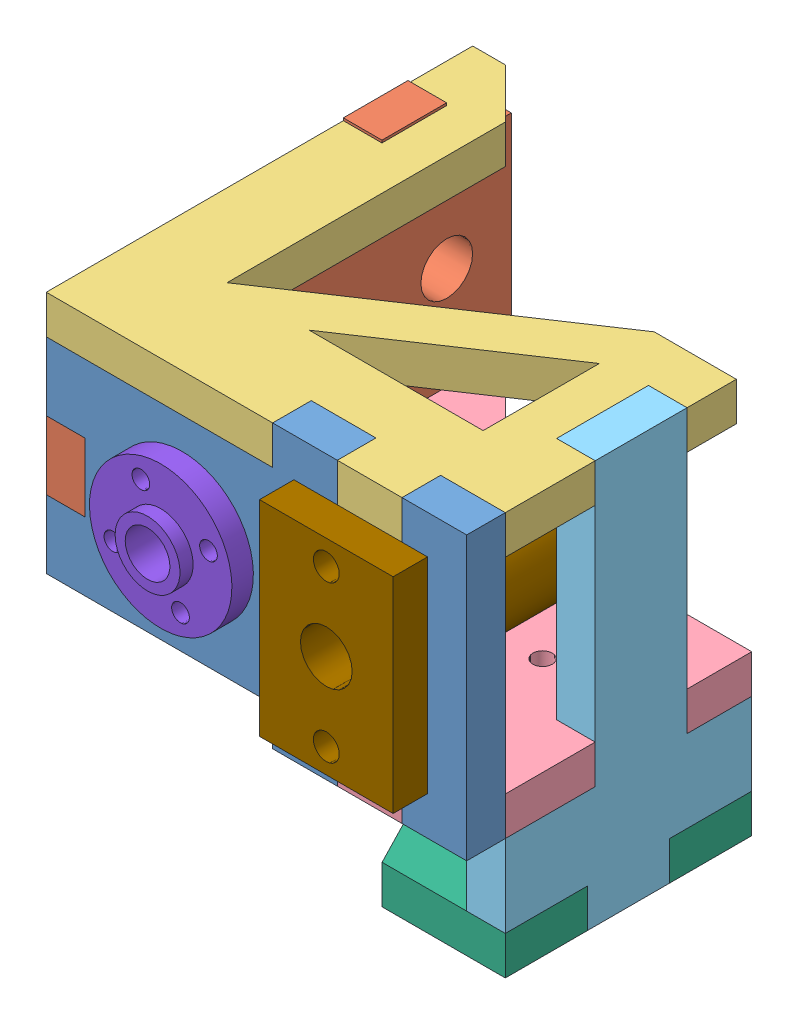
SolidWorks assembly yAssemLeftSide, configuration Default. Lengths in mm.
Overall size (65 62.69 71.28).
9 component instances, 9 part files, 27 mates.
Components (placement in the parent):
- yMountBase-1: yMountBase [Default] at (26.2559 40.0387 54.9751) x (0 -1 0) z (1 0 0) size (42.67 5.97 65)
- xRodHolderFace-1: xRodHolderFace [Default] at (-32.7751 18.9054 49.0061) x (0 1 0) z (-1 0 0) size (44.4 65.93 5.97)
- yBrace-2: yBrace [Default] at (-32.7751 40.0387 19.047) size (65 5.97 65.93)
- yBraceLeft-1: yBraceLeft [Default] at (-32.7751 2.3697 19.047) size (65 5.97 65.93)
- yLeftSideSprocketMount-1: yLeftSideSprocketMount [Default] at (26.2559 -10.3303 49.0061) x (0 1 0) z (0 0 1) size (62.31 5.97 38.1)
- 3mmSprocketHolder-1: 3mmSprocketHolder [Default] at (26.2559 -16.2993 49.0061) x (0 0 -1) z (1 0 0) size (38.1 5.97 26.24)
- 3mmSprocket-1: 3mmSprocket [Default] at (11.0159 -8.2653 28.0061) size (13 8.57 13)
- brassThing-1: brassThing [Default] at (-17.7341 24.1887 58.2951) x (-0.923728 -0.383049 0) z (0.383049 -0.923728 0) size (22.02 10.35 22.02)
- slider-1: slider [Default] at (20.1998 40.0387 60.2951) x (0 -1 0) z (1 0 0) size (31.7 45.2 20.66)
Mates (geometry in assembly coordinates):
- Coincident1: coincident: plane of ? through (18.4701 50.7912 97.883) normal (0 0 1); plane of yMountBase-1 through (26.2559 40.0387 49.0061) normal (0 0 -1)
- Coincident2: coincident: plane of ? through (-20.1799 44.4412 67.924) normal (0 -1 0); plane of yMountBase-1 through (6.2559 45.0387 54.9751) normal (0 1 0)
- Coincident5: coincident: plane of ? through (28.4701 50.7912 97.883) normal (1 0 0); plane of yMountBase-1 through (16.2559 40.0387 54.9751) normal (-1 0 0)
- Coincident6: coincident: plane of ? through (-20.1799 50.7912 67.924) normal (0 1 0); plane of yMountBase-1 through (6.2559 45.0387 54.9751) normal (0 1 0)
- Coincident7: coincident anti-aligned: plane of yMountBase-1 through (26.2559 40.0387 49.0061) normal (0 0 -1); plane of xRodHolderFace-1 through (-38.7441 40.0387 49.0061) normal (0 0 1)
- Coincident8: coincident anti-aligned: plane of yMountBase-1 through (-32.7751 18.9054 49.0061) normal (-1 0 0); plane of xRodHolderFace-1 through (-32.7751 18.9054 49.0061) normal (1 0 0)
- Coincident9: coincident anti-aligned: plane of yMountBase-1 through (-38.7441 18.9054 49.0061) normal (0 1 0); plane of xRodHolderFace-1 through (-38.7441 18.9054 54.9751) normal (0 -1 0)
- Coincident12: coincident anti-aligned: plane of yMountBase-1 through (26.2559 40.0387 49.0061) normal (0 1 0); plane of yBrace-2 through (-32.7751 40.0387 19.047) normal (0 -1 0)
- Coincident13: coincident anti-aligned: plane of xRodHolderFace-1 through (-32.7751 18.9054 49.0061) normal (1 0 0); plane of yBrace-2 through (-32.7751 46.0077 9.047) normal (-1 0 0)
- Coincident14: coincident anti-aligned: plane of xRodHolderFace-1 through (-32.7751 18.9054 49.0061) normal (1 0 0); plane of yBrace-2 through (-32.7751 46.0077 9.047) normal (-1 0 0)
- Coincident15: coincident: line of xRodHolderFace-1 through (-38.7441 46.3887 9.047) axis (0 -1 0); plane of yBrace-2 through (-38.7441 46.0077 9.047) normal (0 0 -1)
- Coincident16: coincident anti-aligned: plane of xRodHolderFace-1 through (-32.7751 18.9054 49.0061) normal (1 0 0); plane of yBraceLeft-1 through (-32.7751 8.3387 9.047) normal (-1 0 0)
- Coincident17: coincident anti-aligned: plane of yMountBase-1 through (26.2559 40.0387 49.0061) normal (0 0 -1); plane of yBraceLeft-1 through (26.2559 8.3387 49.0061) normal (0 0 1)
- Coincident18: coincident aligned: plane of yMountBase-1 through (26.2559 2.3697 54.9751) normal (0 -1 0); plane of yBraceLeft-1 through (-32.7751 2.3697 19.047) normal (0 -1 0)
- Coincident22: coincident anti-aligned: plane of yBraceLeft-1 through (20.2869 -45.5551 35.1061) normal (1 0 0); plane of yLeftSideSprocketMount-1 through (20.2869 -10.3303 49.0061) normal (-1 0 0)
- Coincident23: coincident anti-aligned: plane of yBraceLeft-1 through (26.2559 -45.5551 35.1061) normal (0 0 -1); plane of yLeftSideSprocketMount-1 through (20.2869 2.3697 35.1061) normal (0 0 1)
- Coincident24: coincident anti-aligned: plane of yLeftSideSprocketMount-1 through (20.2869 -10.3303 49.0061) normal (-1 0 0); plane of 3mmSprocketHolder-1 through (20.2869 -10.3303 36.3061) normal (1 0 0)
- Coincident25: coincident anti-aligned: plane of yLeftSideSprocketMount-1 through (20.2869 -10.3303 23.6061) normal (0 0 -1); plane of 3mmSprocketHolder-1 through (20.2869 -10.3303 23.6061) normal (0 0 1)
- Coincident26: coincident anti-aligned: plane of yLeftSideSprocketMount-1 through (20.2869 -10.3303 10.9061) normal (0 -1 0); plane of 3mmSprocketHolder-1 through (26.2559 -10.3303 49.0061) normal (0 1 0)
- Concentric1: concentric anti-aligned: cylinder of 3mmSprocketHolder-1 through (11.0159 -10.3303 28.0061) axis (0 -1 0) radius 1.5; cylinder of 3mmSprocket-1 through (11.0159 -8.2653 28.0061) axis (0 1 0) radius 1.5
- Width1: width aligned: plane of 3mmSprocket-1 through (11.0159 -8.2653 28.0061) normal (0 -1 0); plane of yBraceLeft-1 through (11.0159 0.3047 28.0061) normal (0 1 0); plane of 3mmSprocket-1 through (-32.7751 2.3697 19.047) normal (0 -1 0); plane of 3mmSprocketHolder-1 through (26.2559 -10.3303 49.0061) normal (0 1 0)
- Concentric2: concentric aligned: cylinder of yMountBase-1 through (-17.7341 24.1887 49.0061) axis (0 0 1) radius 5.015; cylinder of brassThing-1 through (-17.7341 24.1887 49.9751) axis (0 0 1) radius 5.015
- Coincident28: coincident anti-aligned: plane of yMountBase-1 through (26.2559 40.0387 54.9751) normal (0 0 1); plane of brassThing-1 through (-17.7341 24.1887 54.9751) normal (0 0 -1)
- Concentric3: concentric aligned: cylinder of yMountBase-1 through (9.8698 24.1887 49.0061) axis (0 0 1) radius 7.5; cylinder of slider-1 through (9.8698 24.1887 15.0951) axis (0 0 1) radius 7.5
- Coincident29: coincident anti-aligned: plane of yMountBase-1 through (26.2559 40.0387 54.9751) normal (0 0 1); plane of slider-1 through (20.1998 40.0387 54.9751) normal (0 0 -1)
- Parallel1: parallel aligned: plane of yMountBase-1 through (26.2559 45.0387 54.9751) normal (0 1 0); plane of slider-1 through (20.1998 40.0387 54.9751) normal (0 1 0)
- Coincident30: coincident anti-aligned: plane of yBraceLeft-1 through (-32.7751 2.3697 19.047) normal (0 -1 0); plane of yLeftSideSprocketMount-1 through (20.2869 2.3697 20.9061) normal (0 1 0)
